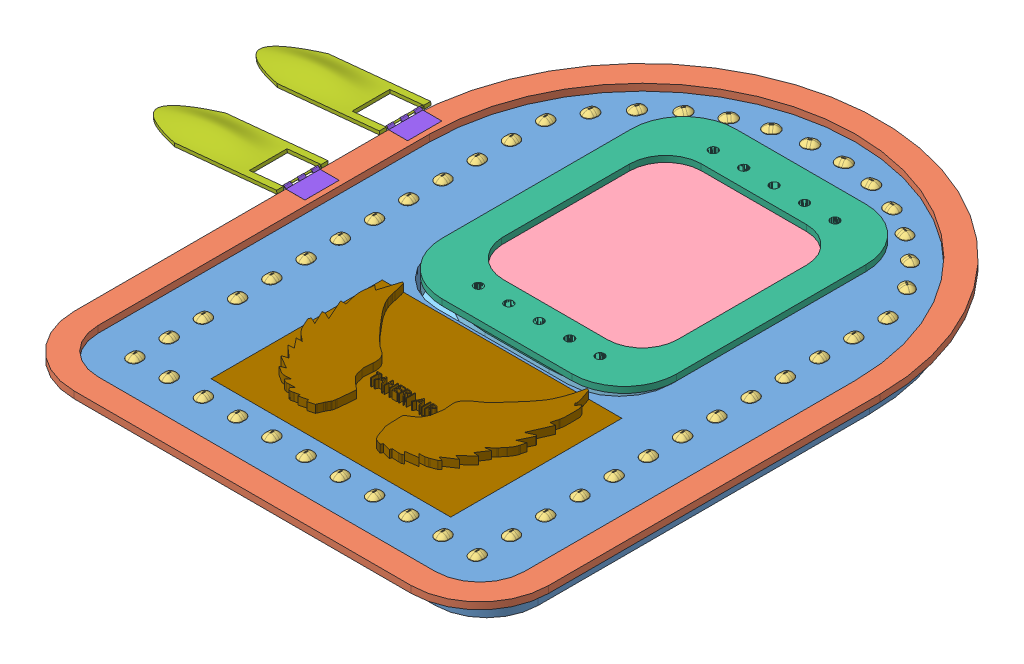
SolidWorks assembly Step Door, configuration Default. Lengths in mm.
Overall size (909.26 80.24 930.91).
61 component instances, 12 part files, 19 mates.
Components (placement in the parent):
- Door Silhoutte-1: Door Silhoutte [Default] at (322.1513 480.4461 664.5477) size (642.62 33.02 880.11)
- Main door frame-1: Main door frame [Default] at (328.6157 513.4661 679.3258) x (1 0 0) z (0 1 0) size (693.42 930.91 10)
- Some dec-1: Some dec [Default] at (-10.1007 487.4987 998.2286) x (-1 0 0) z (0 1 0) size (18.43 22.18 6.72)
- Some dec-2: Some dec [Default] at (39.8993 487.4987 998.2286) x (-1 0 0) z (0 1 0) size (18.43 22.18 6.72)
- Some dec-3: Some dec [Default] at (89.8993 487.4987 998.2286) x (-1 0 0) z (0 1 0) size (18.43 22.18 6.72)
- Some dec-4: Some dec [Default] at (139.8993 487.4987 998.2286) x (-1 0 0) z (0 1 0) size (18.43 22.18 6.72)
- Some dec-5: Some dec [Default] at (189.8993 487.4987 998.2286) x (-1 0 0) z (0 1 0) size (18.43 22.18 6.72)
- Some dec-6: Some dec [Default] at (239.8993 487.4987 998.2286) x (-1 0 0) z (0 1 0) size (18.43 22.18 6.72)
- Some dec-7: Some dec [Default] at (289.8993 487.4987 998.2286) x (-1 0 0) z (0 1 0) size (18.43 22.18 6.72)
- Some dec-8: Some dec [Default] at (339.8993 487.4987 998.2286) x (-1 0 0) z (0 1 0) size (18.43 22.18 6.72)
- Some dec-9: Some dec [Default] at (389.8993 487.4987 998.2286) x (-1 0 0) z (0 1 0) size (18.43 22.18 6.72)
- Some dec-10: Some dec [Default] at (439.8993 487.4987 998.2286) x (-1 0 0) z (0 1 0) size (18.43 22.18 6.72)
- Some dec-11: Some dec [Default] at (489.8993 487.4987 998.2286) x (-1 0 0) z (0 1 0) size (18.43 22.18 6.72)
- Some dec-12: Some dec [Default] at (-10.1007 487.4987 948.2286) x (-1 0 0) z (0 1 0) size (18.43 22.18 6.72)
- Some dec-13: Some dec [Default] at (-10.1007 487.4987 898.2286) x (-1 0 0) z (0 1 0) size (18.43 22.18 6.72)
- Some dec-14: Some dec [Default] at (-10.1007 487.4987 848.2286) x (-1 0 0) z (0 1 0) size (18.43 22.18 6.72)
- Some dec-15: Some dec [Default] at (-10.1007 487.4987 798.2286) x (-1 0 0) z (0 1 0) size (18.43 22.18 6.72)
- Some dec-16: Some dec [Default] at (-10.1007 487.4987 748.2286) x (-1 0 0) z (0 1 0) size (18.43 22.18 6.72)
- Some dec-17: Some dec [Default] at (-10.1007 487.4987 698.2286) x (-1 0 0) z (0 1 0) size (18.43 22.18 6.72)
- Some dec-18: Some dec [Default] at (-10.1007 487.4987 648.2286) x (-1 0 0) z (0 1 0) size (18.43 22.18 6.72)
- Some dec-19: Some dec [Default] at (-10.1007 487.4987 598.2286) x (-1 0 0) z (0 1 0) size (18.43 22.18 6.72)
- Some dec-20: Some dec [Default] at (-10.1007 487.4987 548.2286) x (-1 0 0) z (0 1 0) size (18.43 22.18 6.72)
- Some dec-21: Some dec [Default] at (-10.1007 487.4987 498.2286) x (-1 0 0) z (0 1 0) size (18.43 22.18 6.72)
- Some dec-22: Some dec [Default] at (-10.1007 487.4987 448.2286) x (-1 0 0) z (0 1 0) size (18.43 22.18 6.72)
- Some dec-23: Some dec [Default] at (-10.1007 487.4987 398.2286) x (-1 0 0) z (0 1 0) size (18.43 22.18 6.72)
- Some dec-24: Some dec [Default] at (22.3094 487.4987 342.9276) x (-0.984808 0 -0.173648) z (0 1 0) size (18.43 22.18 6.72)
- Some dec-25: Some dec [Default] at (63.83 487.4987 294.0946) x (-0.939693 0 -0.34202) z (0 1 0) size (18.43 22.18 6.72)
- Some dec-26: Some dec [Default] at (113.1996 487.4987 253.2135) x (-0.866025 0 -0.5) z (0 1 0) size (18.43 22.18 6.72)
- Some dec-27: Some dec [Default] at (168.9182 487.4987 221.5265) x (-0.766044 0 -0.642788) z (0 1 0) size (18.43 22.18 6.72)
- Some dec-28: Some dec [Default] at (229.2926 487.4987 199.9962) x (-0.642788 0 -0.766044) z (0 1 0) size (18.43 22.18 6.72)
- Some dec-29: Some dec [Default] at (292.4885 487.4987 189.277) x (-0.5 0 -0.866025) z (0 1 0) size (18.43 22.18 6.72)
- Some dec-30: Some dec [Default] at (356.5856 487.4987 189.6944) x (-0.34202 0 -0.939693) z (0 1 0) size (18.43 22.18 6.72)
- Some dec-31: Some dec [Default] at (419.6365 487.4987 201.2359) x (-0.173648 0 -0.984808) z (0 1 0) size (18.43 22.18 6.72)
- Some dec-32: Some dec [Default] at (489.8993 487.4987 948.2286) x (-1 0 0) z (0 1 0) size (18.43 22.18 6.72)
- Some dec-33: Some dec [Default] at (489.8993 487.4987 898.2286) x (-1 0 0) z (0 1 0) size (18.43 22.18 6.72)
- Some dec-34: Some dec [Default] at (489.8993 487.4987 848.2286) x (-1 0 0) z (0 1 0) size (18.43 22.18 6.72)
- Some dec-35: Some dec [Default] at (489.8993 487.4987 798.2286) x (-1 0 0) z (0 1 0) size (18.43 22.18 6.72)
- Some dec-36: Some dec [Default] at (489.8993 487.4987 748.2286) x (-1 0 0) z (0 1 0) size (18.43 22.18 6.72)
- Some dec-37: Some dec [Default] at (489.8993 487.4987 698.2286) x (-1 0 0) z (0 1 0) size (18.43 22.18 6.72)
- Some dec-38: Some dec [Default] at (489.8993 487.4987 648.2286) x (-1 0 0) z (0 1 0) size (18.43 22.18 6.72)
- Some dec-39: Some dec [Default] at (489.8993 487.4987 598.2286) x (-1 0 0) z (0 1 0) size (18.43 22.18 6.72)
- Some dec-40: Some dec [Default] at (489.8993 487.4987 548.2286) x (-1 0 0) z (0 1 0) size (18.43 22.18 6.72)
- Some dec-41: Some dec [Default] at (489.8993 487.4987 498.2286) x (-1 0 0) z (0 1 0) size (18.43 22.18 6.72)
- Some dec-42: Some dec [Default] at (489.8993 487.4987 448.2286) x (-1 0 0) z (0 1 0) size (18.43 22.18 6.72)
- Some dec-43: Some dec [Default] at (489.8993 487.4987 398.2286) x (-1 0 0) z (0 1 0) size (18.43 22.18 6.72)
- Some dec-44: Some dec [Default] at (479.7254 487.4987 223.5507) x (0 0 -1) z (0 1 0) size (18.43 22.18 6.72)
- Some dec-45: Some dec [Default] at (535.0264 487.4987 255.9608) x (0.173648 0 -0.984808) z (0 1 0) size (18.43 22.18 6.72)
- Some dec-46: Some dec [Default] at (583.8594 487.4987 297.4815) x (0.34202 0 -0.939693) z (0 1 0) size (18.43 22.18 6.72)
- Some dec-47: Some dec [Default] at (624.7405 487.4987 346.8511) x (0.5 0 -0.866025) z (0 1 0) size (18.43 22.18 6.72)
- Window As-1: Window As [Default] at (351.1513 510.7449 559.9171) x (1 0 0) z (0 1 0) size (528.81 658.71 63.76) (flexible)
  - Window, Normal-1: Window, Normal [Default] at (-192.0812 -28.7605 -12.5188) size (303.99 343.6 6.35)
  - Part2 (2)-1: Part2 (2) [Default] at (-193.4544 -38.9205 -45.5388) size (342.9 429.26 40.89)
  - Front Frame-1: Front Frame [Default] at (135.4543 -38.9205 11.6112) x (-1 0 0) z (0 0 -1) size (342.9 429.26 32.01)
  - Window closer-1: Window closer [Default<As Machined>] at (134.081 232.3515 -21.4088) x (-1 0 0) z (0 0 -1) size (303.99 343.6 21.59) (hidden)
  - Cover-1: Cover [Default] at origin size (528.81 605.62 40) (hidden)
  - Part9^Window As-1: Part9^Window As [Default] at (-193.4544 -38.9205 -45.5388) x (-1 0 0) z (0 0 -1) (virtual)
- Hopeful Hinge-1: Hopeful Hinge [Default] at (38.5643 528.9161 517.5027) x (0 0 1) z (-0.096746 0.995309 0) size (77.25 216.21 16.05)
- Exit Hinge-1: Exit Hinge [Default] at (-343.5402 523.4661 480.8275) x (-1 0 0) z (0 -1 0) size (32.61 50 3.02)
- TA-1: TA [Default] at (325.8413 513.4761 889.6027) x (0 0 -1) z (0 1 0) size (251.79 350 12.37)
- Hopeful Hinge-3: Hopeful Hinge [Default] at (38.5643 528.9161 667.5027) x (0 0 1) z (-0.096746 0.995309 0) size (77.25 216.21 16.05)
- Exit Hinge-3: Exit Hinge [Default] at (-343.5402 523.4661 630.8275) x (-1 0 0) z (0 -1 0) size (32.61 50 3.02)
Mates (geometry in assembly coordinates):
- Width1: width aligned: plane of Door Silhoutte-1 through (643.4613 505.8461 664.5477) normal (1 0 0); plane of Main door frame-1 through (0.8413 505.8461 664.5477) normal (-1 0 0); plane of Door Silhoutte-1 through (668.8613 523.4661 679.3258) normal (1 0 0); plane of Main door frame-1 through (-24.5587 523.4661 679.3258) normal (-1 0 0)
- Parallel1: parallel aligned: line of Door Silhoutte-1 through (75.7713 480.4461 1104.6027) axis (1 0 0); line of Main door frame-1 through (75.7713 513.4661 1104.6027) axis (1 0 0)
- Coincident3: coincident anti-aligned: plane of Door Silhoutte-1 through (75.7713 513.4661 1029.6727) normal (0 1 0); plane of Main door frame-1 through (328.6157 513.4661 679.3258) normal (0 -1 0)
- Coincident6: coincident aligned: line of Door Silhoutte-1 through (75.7713 513.4661 1104.6027) axis (1 0 0); line of Main door frame-1 through (75.7713 513.4661 1104.6027) axis (1 0 0)
- Coincident7: coincident anti-aligned: plane of Door Silhoutte-1 through (75.7713 513.4661 1029.6727) normal (0 1 0); plane of Some dec-1 through (63.3424 513.4661 1040.8185) normal (0 -1 0)
- Distance1: distance = 50 mm: point of Some dec-1; line of Main door frame-1 through (75.7713 513.4661 1104.6027) axis (1 0 0)
- Distance2: distance = 50 mm: line of Some dec-1 through (60.8413 513.4661 1046.2059) axis (0 0 -1); line of Main door frame-1 through (10.8413 513.4661 555.8027) axis (0 0 1)
- Width2: width anti-aligned: plane of Window As-1/Part2 (2)-1 through (493.6013 474.0961 677.4682) normal (1 0 0); plane of Window As-1/Part2 (2)-1 through (150.7013 474.0961 400.6082) normal (-1 0 0); plane of Door Silhoutte-1 through (493.6013 505.8461 664.5477) normal (-1 0 0); plane of Door Silhoutte-1 through (150.7013 505.8461 664.5477) normal (1 0 0)
- Width3: width anti-aligned: plane of Window As-1/Part2 (2)-1 through (226.9013 474.0961 753.6682) normal (0 0 1); plane of Window As-1/Part2 (2)-1 through (275.6693 499.4961 338.9532) normal (0 0 -1); plane of Door Silhoutte-1 through (322.1513 505.8461 760.9407) normal (0 0 -1); plane of Door Silhoutte-1 through (322.1513 505.8461 331.6807) normal (0 0 1)
- Coincident10: coincident anti-aligned: plane of Door Silhoutte-1 through (75.7713 513.4661 1029.6727) normal (0 1 0); plane of Window As-1/Front Frame-1 through (226.9013 513.4661 677.4682) normal (0 -1 0)
- Coincident12: coincident anti-aligned: plane of Main door frame-1 through (328.6157 523.4661 679.3258) normal (0 1 0); plane of Exit Hinge-1 through (-343.5402 523.4661 480.8275) normal (0 -1 0)
- Parallel2: parallel aligned: line of Main door frame-1 through (10.8413 523.4661 555.8027) axis (0 0 1); line of Exit Hinge-1 through (3.2864 523.4661 530.0027) axis (0 0 1)
- Coincident14: coincident anti-aligned: line of Main door frame-1 through (-24.5587 523.4661 555.8027) axis (0 0 1); line of Exit Hinge-1 through (-24.5587 523.4661 570.0027) axis (0 0 -1)
- Distance3: distance = 560 mm: line of Exit Hinge-1 through (3.2864 523.4661 580.0027) axis (-1 0 0); line of Main door frame-1 through (75.7713 523.4661 1140.0027) axis (1 0 0)
- Coincident15: coincident anti-aligned: plane of Door Silhoutte-1 through (75.7713 513.4661 1029.6727) normal (0 1 0); plane of TA-1 through (296.4683 513.4661 907.962) normal (0 -1 0)
- Distance4: distance = 90 mm: line of TA-1 through (150.8413 513.4661 1014.6027) axis (1 0 0); line of Door Silhoutte-1 through (75.7713 513.4661 1104.6027) axis (1 0 0)
- Distance5: distance = 150 mm: line of TA-1 through (150.8413 513.4661 764.6027) axis (0 0 1); line of Door Silhoutte-1 through (0.8413 513.4661 545.8027) axis (0 0 1)
- Concentric2: concentric aligned: cylinder of Hopeful Hinge-1 through (-27.8103 524.9761 523.9672) axis (0 0 1) radius 1.25; circle of Exit Hinge-1
- Width5: width anti-aligned: plane of Exit Hinge-1 through (-27.8103 524.9761 530.0027) normal (0 0 -1); plane of Exit Hinge-1 through (-27.8103 524.9761 580.0027) normal (0 0 1); plane of Hopeful Hinge-1 through (38.0806 533.8926 527.5027) normal (0 0 1); plane of Hopeful Hinge-1 through (38.0806 533.8926 582.5027) normal (0 0 -1)
